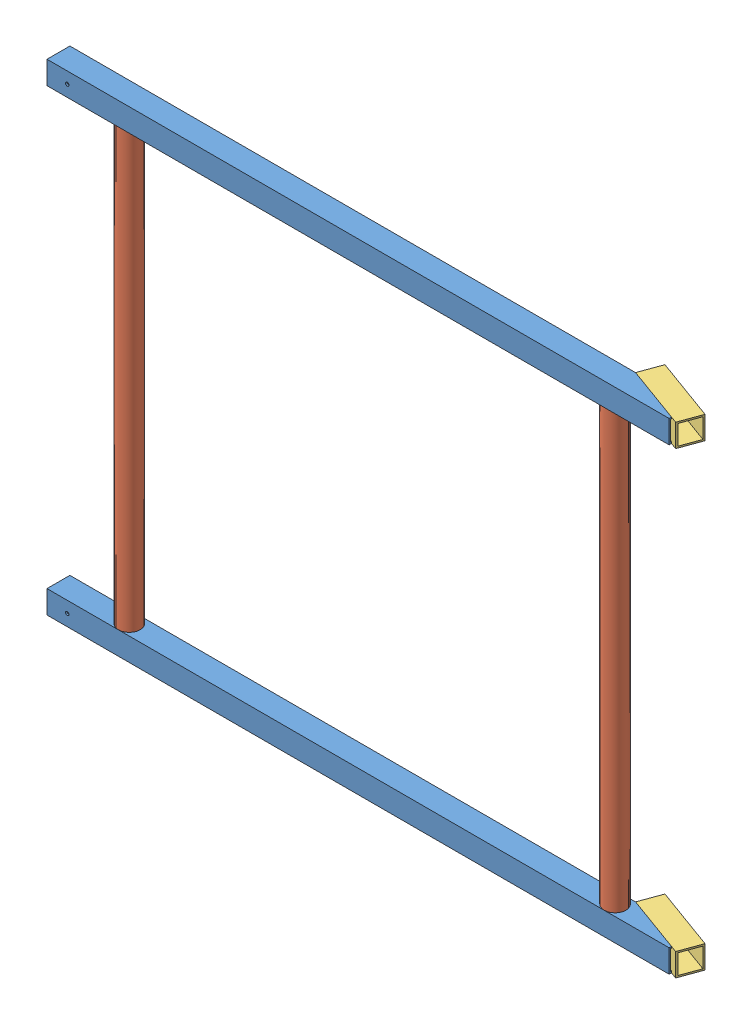
SolidWorks assembly GE-20310, configuration Default. Lengths in mm.
Overall size (1234.4 933.45 86.25).
6 component instances, 3 part files, 19 mates.
Components (placement in the parent):
- GE-20310-01-1: GE-20310-01 [Default] at (-609.6 0 0) size (1206.5 44.45 44.45)
- GE-20310-01-2: GE-20310-01 [Default] at (-609.6 889 0) size (1206.5 44.45 44.45)
- GE-20310-02-1: GE-20310-02 [Default] at (-471.043 44.45 -21.082) x (-1 0 0) z (0 0 -1) size (42.16 844.55 42.16)
- GE-20310-02-2: GE-20310-02 [Default] at (471.043 44.45 -21.082) size (42.16 844.55 42.16)
- GE-20310-03-1: GE-20310-03 [Default] at (487.3949 889 -44.479) x (0.939693 0 0.34202) z (-0.34202 0 0.939693) size (130.05 44.45 44.45)
- GE-20310-03-2: GE-20310-03 [Default] at (487.3949 0 -44.479) x (0.939693 0 0.34202) z (-0.34202 0 0.939693) size (130.05 44.45 44.45)
Mates (geometry in assembly coordinates):
- Coincident1: coincident anti-aligned: plane of GE-20310-01-1 through (609.6 44.45 0) normal (0 1 0); plane of GE-20310-02-1 through (-471.043 44.45 -21.082) normal (0 -1 0)
- Tangent1: tangent aligned: plane of GE-20310-01-1 through (609.6 0 0) normal (0 0 1); cylinder of GE-20310-02-1 through (-471.043 889 -21.082) axis (0 -1 0) radius 21.082
- Tangent2: tangent aligned: plane of GE-20310-01-1 through (609.6 0 0) normal (0 0 1); cylinder of GE-20310-02-2 through (471.043 889 -21.082) axis (0 -1 0) radius 21.082
- Coincident4: coincident anti-aligned: plane of GE-20310-01-1 through (609.6 44.45 0) normal (0 1 0); plane of GE-20310-02-2 through (471.043 44.45 -21.082) normal (0 -1 0)
- Tangent3: tangent aligned: plane of GE-20310-01-2 through (609.6 889 0) normal (0 0 1); cylinder of GE-20310-02-1 through (-471.043 889 -21.082) axis (0 -1 0) radius 21.082
- Coincident6: coincident anti-aligned: plane of GE-20310-01-2 through (609.6 889 0) normal (0 -1 0); plane of GE-20310-02-1 through (-471.043 889 -21.082) normal (0 1 0)
- Coincident7: coincident anti-aligned: plane of GE-20310-01-1 through (609.6 0 0) normal (0.34202 0 -0.939693); plane of GE-20310-03-2 through (609.6 0 0) normal (-0.34202 0 0.939693)
- Coincident8: coincident aligned: plane of GE-20310-01-1 through (609.6 44.45 0) normal (0 1 0); plane of GE-20310-03-2 through (609.6 44.45 0) normal (0 1 0)
- Coincident9: coincident: plane of GE-20310-01-2 through (609.6 889 0) normal (0 0 1); line of GE-20310-03-1 through (44.45 609.6 933.45) axis (0 0 -1)
- Coincident10: coincident anti-aligned: plane of GE-20310-01-2 through (609.6 889 0) normal (0.34202 0 -0.939693); plane of GE-20310-03-1 through (609.6 889 0) normal (-0.34202 0 0.939693)
- Coincident11: coincident aligned: plane of GE-20310-01-2 through (609.6 933.45 0) normal (0 1 0); plane of GE-20310-03-1 through (609.6 933.45 0) normal (0 1 0)
- Distance1: distance = 117.475 mm: cylinder of GE-20310-02-1 through (-471.043 889 -21.082) axis (0 -1 0) radius 21.082; plane of GE-20310-01-1 through (-609.6 0 0) normal (-1 0 0)
- Coincident14: coincident aligned: plane of GE-20310-01-1 through (-609.6 0 0) normal (-1 0 0); plane of GE-20310-01-2 through (-609.6 889 0) normal (-1 0 0)
- Coincident15: coincident aligned: plane of GE-20310-01-1 through (609.6 0 0) normal (0 0 1)
- Coincident16: coincident anti-aligned: plane of GE-20310-01-1 through (609.6 0 0) normal (0 -1 0)
- Symmetric1: symmetric aligned: plane of GE-20310-02-1 through (-471.043 44.45 -21.082) normal (-1 0 0); plane of GE-20310-02-2 through (471.043 44.45 -21.082) normal (1 0 0)
- Symmetric2: symmetric aligned: line of GE-20310-01-2 through (44.45 -609.6 933.45) axis (0 0 -1); line of GE-20310-03-1 through (44.45 609.6 933.45) axis (0 0 -1)
- Parallel1: parallel anti-aligned: plane of GE-20310-02-1 through (-471.043 44.45 -21.082) normal (-1 0 0)
- Coincident17: coincident aligned: plane of GE-20310-03-1 through (609.6 889 0) normal (0.939693 0 0.34202); plane of GE-20310-03-2 through (609.6 0 0) normal (0.939693 0 0.34202)
